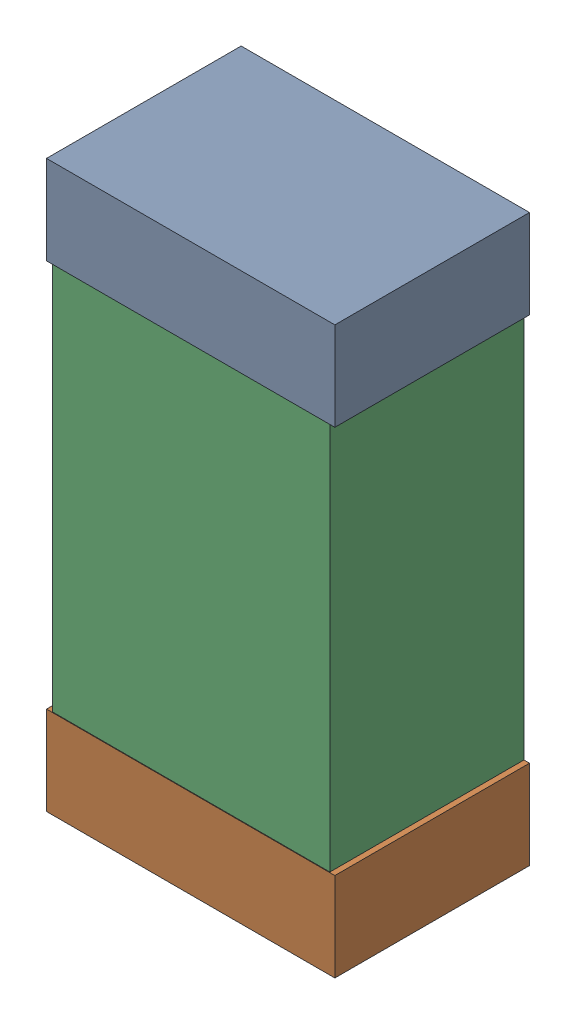
SolidWorks assembly C12, configuration Default. Lengths in mm.
Overall size (0.52 1.02 0.35).
6 component instances, 2 part files, 0 mates.
Components (placement in the parent):
- 870941120-1: 870941120 [Default] at (53.4408 26.4882 0) size (0.52 0.16 0.35)
  - Extruded_3-1: Extruded_3 [Default] at origin size (0.52 0.16 0.35)
- 870941120-2: 870941120 [Default] at (53.4408 25.6282 0) size (0.52 0.16 0.35)
  - Extruded_3-1: Extruded_3 [Default] at origin size (0.52 0.16 0.35)
- 870941280-1: 870941280 [Default] at (53.4408 26.0582 0) size (0.5 1 0.35)
  - Extruded_4-1: Extruded_4 [Default] at origin size (0.5 1 0.35)
